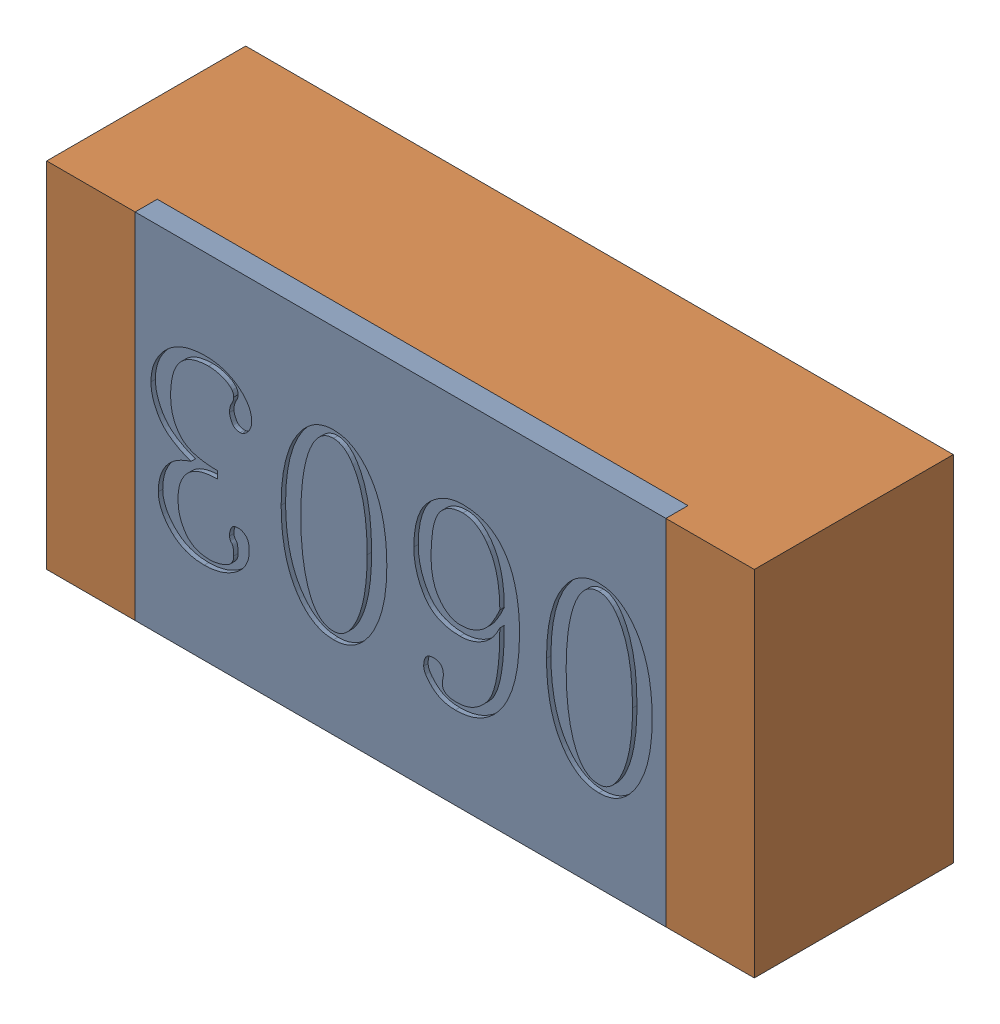
SolidWorks assembly RC3, configuration 默认. Lengths in mm.
Overall size (1.6 0.8 0.45).
3 component instances, 2 part files, 0 mates.
Components (placement in the parent):
- RC3-subassembly-1-1: RC3-subassembly-1 [默认] at (18.2879 12.3189 0) x (-1 0 0) z (0 0 1) size (1.6 0.8 0.45)
  - R0603-1: R0603 [默认] at origin size (1.2 0.8 0.05)
  - R0603-1-1: R0603-1 [默认] at origin size (1.6 0.8 0.45)
